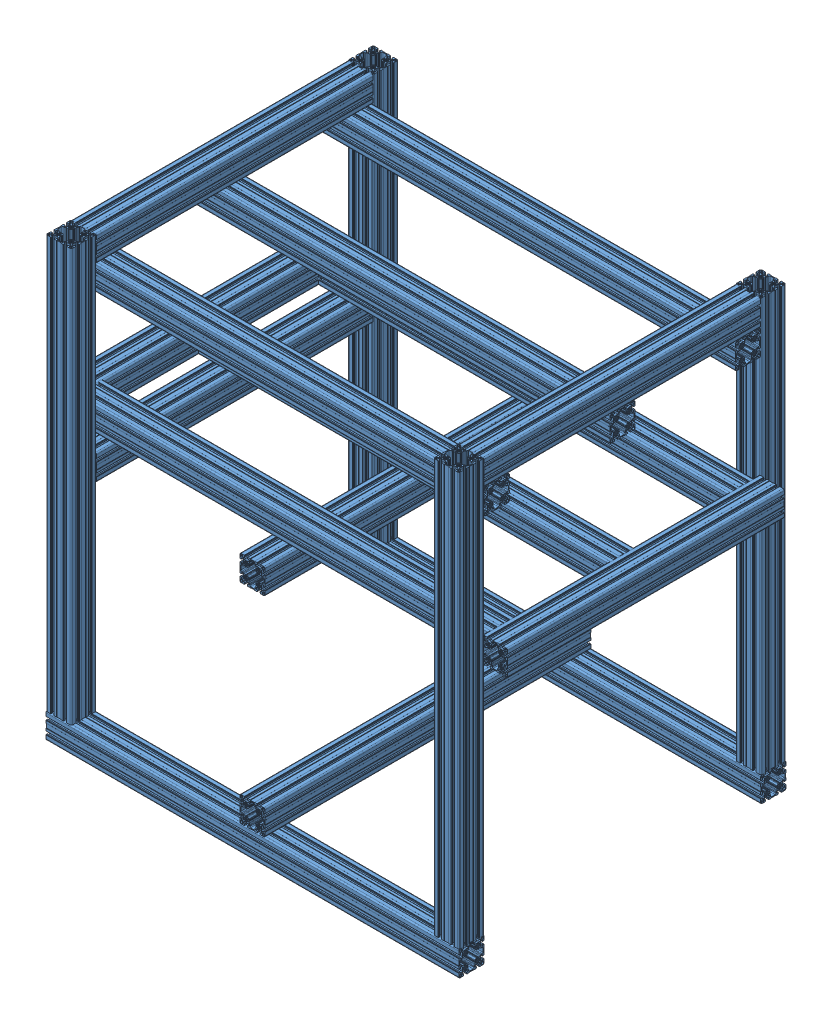
SolidWorks assembly Sheetpress, configuration Default. Lengths in mm.
Overall size (1637.66 1559.98 1164.96).
19 component instances, 1 part files, 30 mates.
Components (placement in the parent):
- Profile 90x90L Bosch-Type slot 10-1: Profile 90x90L Bosch-Type slot 10 [Verticals - 1470mm  - 4 cuts in 6m length] at (-697.0101 824.9801 493.49) x (1 0 0) z (0 -1 0) size (89.98 89.98 1470)
- Profile 90x90L Bosch-Type slot 10-2: Profile 90x90L Bosch-Type slot 10 [Verticals - 1470mm  - 4 cuts in 6m length] at (-697.0101 824.9801 -493.49) x (1 0 0) z (0 1 0) size (89.98 89.98 1470)
- Profile 90x90L Bosch-Type slot 10-3: Profile 90x90L Bosch-Type slot 10 [Verticals - 1470mm  - 4 cuts in 6m length] at (697.0101 824.9801 493.49) x (-1 0 0) z (0 1 0) size (89.98 89.98 1470)
- Profile 90x90L Bosch-Type slot 10-4: Profile 90x90L Bosch-Type slot 10 [Verticals - 1470mm  - 4 cuts in 6m length] at (697.0101 824.9801 -493.49) x (-1 0 0) z (0 -1 0) size (89.98 89.98 1470)
- Profile 90x90L Bosch-Type slot 10-5: Profile 90x90L Bosch-Type slot 10 [Horizontals FRAME- 985mm  - 6 cuts in 6m length] at (-697.0101 796.1848 0) size (89.98 89.98 985)
- Profile 90x90L Bosch-Type slot 10-6: Profile 90x90L Bosch-Type slot 10 [Verticals - 1470mm  - 4 cuts in 6m length] at (0 0.99 530.49) x (0 0 1) z (-1 0 0) size (89.98 89.98 1470)
- Profile 90x90L Bosch-Type slot 10-9: Profile 90x90L Bosch-Type slot 10 [Horizontals FRAME- 985mm  - 6 cuts in 6m length] at (-697.0101 1470.99 0) size (89.98 89.98 985)
- Profile 90x90L Bosch-Type slot 10-11: Profile 90x90L Bosch-Type slot 10 [Horizontals FRAME- 985mm  - 6 cuts in 6m length] at (-780.8393 924.7407 0) size (89.98 89.98 985)
- Profile 90x90L Bosch-Type slot 10-12: Profile 90x90L Bosch-Type slot 10 [Verticals - 1470mm  - 4 cuts in 6m length] at (0 924.7407 433.5798) x (0 0 -1) z (1 0 0) size (89.98 89.98 1470)
- Profile 90x90L Bosch-Type slot 10-15: Profile 90x90L Bosch-Type slot 10 [Horizontals FRAME- 985mm  - 6 cuts in 6m length] at (780.8393 924.7407 0) x (-1 0 0) z (0 0 -1) size (89.98 89.98 985)
- Profile 90x90L Bosch-Type slot 10-17: Profile 90x90L Bosch-Type slot 10 [Base 1160mm  - 5 cuts in 6m length] at (-7.0001 90.9701 2.4801) size (89.98 89.98 1160)
- Profile 90x90L Bosch-Type slot 10-20: Profile 90x90L Bosch-Type slot 10 [Verticals - 1470mm  - 4 cuts in 6m length] at (0 924.7407 7.0001) x (0 0 -1) z (1 0 0) size (89.98 89.98 1470)
- Profile 90x90L Bosch-Type slot 10-18: Profile 90x90L Bosch-Type slot 10 [Verticals - 1470mm  - 4 cuts in 6m length] at (0 1381.01 440.5099) x (0 0 1) z (-1 0 0) size (89.98 89.98 1470)
- Profile 90x90L Bosch-Type slot 10-21: Profile 90x90L Bosch-Type slot 10 [Verticals - 1470mm  - 4 cuts in 6m length] at (0 1381.01 7.0001) x (0 0 -1) z (1 0 0) size (89.98 89.98 1470)
- Profile 90x90L Bosch-Type slot 10-22: Profile 90x90L Bosch-Type slot 10 [Base 1160mm  - 5 cuts in 6m length] at (-7.0001 834.7607 2.4801) size (89.98 89.98 1160)
- Profile 90x90L Bosch-Type slot 10-23: Profile 90x90L Bosch-Type slot 10 [Verticals - 1470mm  - 4 cuts in 6m length] at (0 0.99 -530.49) x (0 0 -1) z (1 0 0) size (89.98 89.98 1470)
- Profile 90x90L Bosch-Type slot 10-24: Profile 90x90L Bosch-Type slot 10 [Verticals - 1470mm  - 4 cuts in 6m length] at (0 924.7407 -433.5798) x (0 0 1) z (-1 0 0) size (89.98 89.98 1470)
- Profile 90x90L Bosch-Type slot 10-25: Profile 90x90L Bosch-Type slot 10 [Verticals - 1470mm  - 4 cuts in 6m length] at (0 1381.01 -440.5099) x (0 0 -1) z (1 0 0) size (89.98 89.98 1470)
- Profile 90x90L Bosch-Type slot 10-26: Profile 90x90L Bosch-Type slot 10 [Horizontals FRAME- 985mm  - 6 cuts in 6m length] at (697.0101 1470.99 0) x (-1 0 0) z (0 0 -1) size (89.98 89.98 985)
Mates (geometry in assembly coordinates):
- Parallel1: parallel aligned: plane of Profile 90x90L Bosch-Type slot 10-1 through (-697.0101 824.9801 493.49) normal (0 0 1); plane of assembly through (0 0 0) normal (0 0 1)
- Coincident4: coincident aligned: plane of Profile 90x90L Bosch-Type slot 10-1; plane of Profile 90x90L Bosch-Type slot 10-5 through (-690.01 796.1848 0) normal (1 0 0)
- Coincident5: coincident aligned: plane of Profile 90x90L Bosch-Type slot 10-5 through (-697.0101 796.1848 0) normal (0 0 1); plane of assembly through (0 0 0) normal (0 0 1)
- Coincident14: coincident anti-aligned: plane of Profile 90x90L Bosch-Type slot 10-6 through (0 0.99 530.49) normal (-1 0 0); plane of assembly through (0 0 0) normal (1 0 0)
- Coincident16: coincident aligned: plane of Profile 90x90L Bosch-Type slot 10-1 through (-697.0101 824.9801 537.49) normal (0 0 1); plane of Profile 90x90L Bosch-Type slot 10-6 through (0 0.99 537.49) normal (0 0 1)
- Coincident19: coincident aligned: plane of Profile 90x90L Bosch-Type slot 10-5 through (-735 795.1947 492.5) normal (-1 0 0); plane of Profile 90x90L Bosch-Type slot 10-9 through (-735 1470 492.5) normal (-1 0 0)
- Coincident20: coincident aligned: plane of Profile 90x90L Bosch-Type slot 10-5 through (-697.0101 796.1848 0) normal (0 0 1); plane of Profile 90x90L Bosch-Type slot 10-9 through (-697.0101 1470.99 0) normal (0 0 1)
- Coincident21: coincident aligned: plane of Profile 90x90L Bosch-Type slot 10-1 through (-734.51 1559.9801 529.49) normal (0 1 0); plane of Profile 90x90L Bosch-Type slot 10-9 through (-645.02 1559.9801 492.5) normal (0 1 0)
- Coincident22: coincident aligned: plane of Profile 90x90L Bosch-Type slot 10-11 through (-766.8392 1012.7407 492.5) normal (0 1 0); plane of Profile 90x90L Bosch-Type slot 10-12 through (735 1012.7407 419.5797) normal (0 1 0)
- Coincident24: coincident aligned: plane of Profile 90x90L Bosch-Type slot 10-11 through (-780.8393 924.7407 0) normal (0 0 1); plane of assembly through (0 0 0) normal (0 0 1)
- Coincident25: coincident aligned: plane of Profile 90x90L Bosch-Type slot 10-12 through (0 924.7407 433.5798) normal (1 0 0); plane of assembly through (0 0 0) normal (1 0 0)
- Coincident33: coincident aligned: plane of Profile 90x90L Bosch-Type slot 10-17 through (0 90.9701 2.4801) normal (1 0 0); plane of assembly through (0 0 0) normal (1 0 0)
- Coincident35: coincident: plane of Profile 90x90L Bosch-Type slot 10-1 through (-645.02 89.9801 492.5) normal (0 0 -1); point of Profile 90x90L Bosch-Type slot 10-9
- Coincident36: coincident anti-aligned: plane of Profile 90x90L Bosch-Type slot 10-1 through (-734.51 89.9801 529.49) normal (0 -1 0); plane of Profile 90x90L Bosch-Type slot 10-6 through (-735 89.9801 582.4801) normal (0 1 0)
- Coincident37: coincident anti-aligned: plane of Profile 90x90L Bosch-Type slot 10-6 through (-735 0 582.4801) normal (0 -1 0); plane of assembly through (0 0 0) normal (0 1 0)
- Coincident38: coincident aligned: plane of Profile 90x90L Bosch-Type slot 10-1 through (-735 89.9801 492.5) normal (-1 0 0); plane of Profile 90x90L Bosch-Type slot 10-6 through (-735 36.99 492.99) normal (-1 0 0)
- Coincident39: coincident anti-aligned: plane of Profile 90x90L Bosch-Type slot 10-6 through (-735 89.9801 582.4801) normal (0 1 0); plane of Profile 90x90L Bosch-Type slot 10-17 through (44.99 89.9801 582.4801) normal (0 -1 0)
- Coincident40: coincident aligned: plane of Profile 90x90L Bosch-Type slot 10-12 through (735 1013.7308 381.5897) normal (0 1 0); plane of Profile 90x90L Bosch-Type slot 10-20 through (735 1013.7308 -44.99) normal (0 1 0)
- Coincident41: coincident anti-aligned: plane of Profile 90x90L Bosch-Type slot 10-20 through (0 924.7407 0) normal (0 0 -1); plane of assembly through (0 0 0) normal (0 0 1)
- Coincident42: coincident aligned: plane of Profile 90x90L Bosch-Type slot 10-20 through (0 924.7407 7.0001) normal (1 0 0); plane of assembly through (0 0 0) normal (1 0 0)
- Coincident43: coincident aligned: plane of Profile 90x90L Bosch-Type slot 10-21 through (0 1381.01 7.0001) normal (1 0 0); plane of assembly through (0 0 0) normal (1 0 0)
- Coincident45: coincident anti-aligned: plane of Profile 90x90L Bosch-Type slot 10-21 through (0 1381.01 0) normal (0 0 -1); plane of assembly through (0 0 0) normal (0 0 1)
- Coincident48: coincident anti-aligned: plane of Profile 90x90L Bosch-Type slot 10-1 through (-645.02 89.9801 492.5) normal (0 0 -1); plane of Profile 90x90L Bosch-Type slot 10-18 through (-735 1380.0199 492.5) normal (0 0 1)
- Coincident49: coincident aligned: plane of Profile 90x90L Bosch-Type slot 10-6 through (0 0.99 530.49) normal (-1 0 0); plane of Profile 90x90L Bosch-Type slot 10-18 through (0 1381.01 440.5099) normal (-1 0 0)
- Coincident50: coincident aligned: plane of Profile 90x90L Bosch-Type slot 10-18; plane of Profile 90x90L Bosch-Type slot 10-21
- Coincident51: coincident anti-aligned: plane of Profile 90x90L Bosch-Type slot 10-9 through (-645.02 1470 492.5) normal (0 -1 0); plane of Profile 90x90L Bosch-Type slot 10-18 through (-735 1470 492.5) normal (0 1 0)
- Coincident52: coincident aligned: plane of Profile 90x90L Bosch-Type slot 10-17 through (-7.0001 90.9701 2.4801) normal (0 0 1); plane of Profile 90x90L Bosch-Type slot 10-22 through (-7.0001 834.7607 2.4801) normal (0 0 1)
- Coincident53: coincident aligned: plane of Profile 90x90L Bosch-Type slot 10-6 through (-735 0 582.4801) normal (0 0 1); plane of Profile 90x90L Bosch-Type slot 10-17 through (-44.5 126.9701 582.4801) normal (0 0 1)
- Coincident54: coincident anti-aligned: plane of Profile 90x90L Bosch-Type slot 10-12 through (735 923.7507 381.5897) normal (0 -1 0); plane of Profile 90x90L Bosch-Type slot 10-22 through (44.99 923.7507 582.4801) normal (0 1 0)
- Coincident55: coincident aligned: plane of Profile 90x90L Bosch-Type slot 10-22 through (0 834.7607 2.4801) normal (1 0 0); plane of assembly through (0 0 0) normal (1 0 0)
